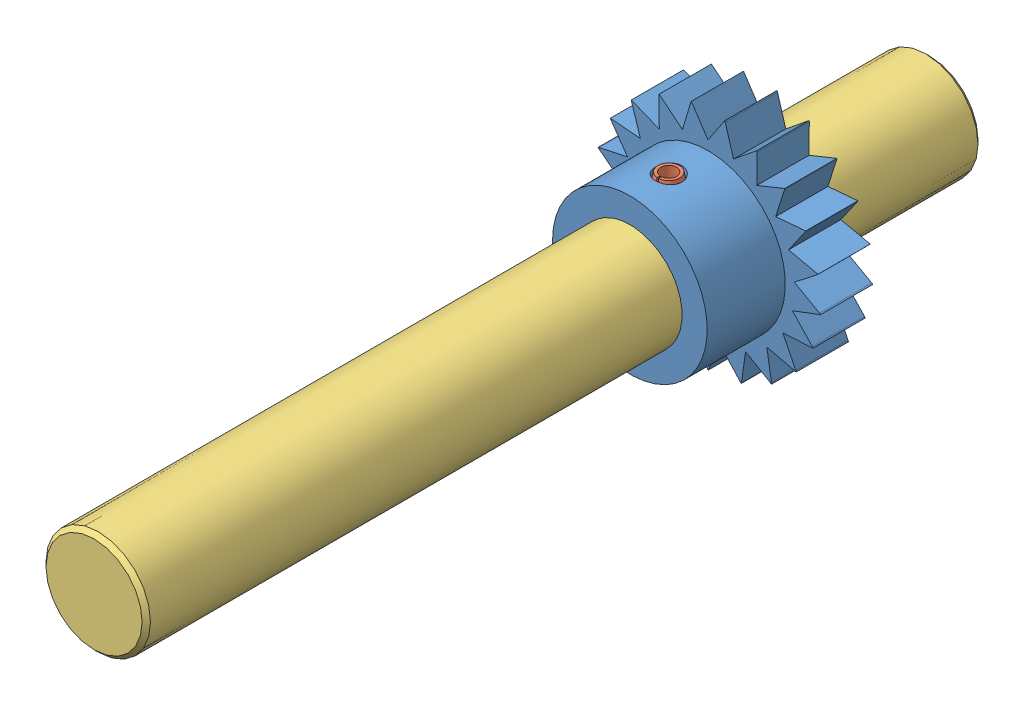
SolidWorks assembly 24 tooth Gear, configuration Default. Lengths in mm.
Overall size (13.68 13.64 50.8).
3 component instances, 3 part files, 4 mates.
Components (placement in the parent):
- 24 tooth Gear-1: 24 tooth Gear [Default] at (-2.6162 11.7892 -10.5656) size (13.68 13.64 7.92)
- Spring Pin Slotted_AI-2: Spring Pin Slotted_AI [SPS 0.0625x0.375] at (-2.6162 7.0394 -5.003) x (0 1 0) z (0 0 1) size (9.53 1.57 1.57)
- Sample Gear Shaft 24 tooth-1: Sample Gear Shaft 24 tooth [Default] at (-2.6162 11.7892 -20.878) x (0 0 -1) z (1 0 0) size (50.8 6.35 6.35)
Mates (geometry in assembly coordinates):
- Concentric1: concentric: cylinder of 24 tooth Gear-1 through (-2.6162 4.9312 -5.003) axis (0 1 0) radius 0.8001; cylinder of Spring Pin Slotted_AI-2 through (-2.6162 -15.1856 -5.003) axis (0 -1 0) radius 0.7874
- Concentric2: concentric aligned: cylinder of 24 tooth Gear-1 through (-2.6162 4.9312 -5.003) axis (0 1 0) radius 0.8001; cylinder of Sample Gear Shaft 24 tooth-1 through (-2.6162 8.6142 -5.003) axis (0 1 0) radius 0.8001
- Concentric3: concentric aligned: cylinder of 24 tooth Gear-1 through (-2.6162 11.7892 -17.351) axis (0 0 -1) radius 3.175; cylinder of Sample Gear Shaft 24 tooth-1 through (-2.6162 11.7892 29.922) axis (0 0 -1) radius 3.175
- Distance2: distance = 4.7498 mm anti-aligned: plane of Spring Pin Slotted_AI-2 through (-3.2766 7.0394 -5.003) normal (0 -1 0); plane of 24 tooth Gear-1 through (-2.6162 11.7892 -10.5656) normal (0 1 0)
